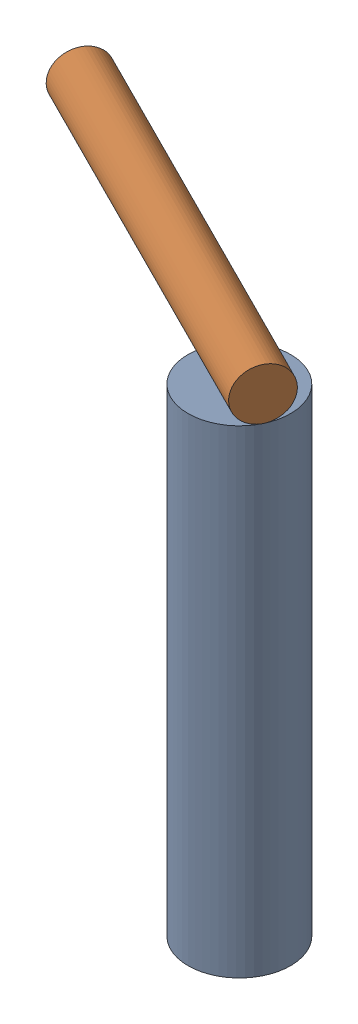
SolidWorks assembly 01-098-00-0, configuration Default. Lengths in mm.
Overall size (73.36 99.52 44.78).
2 component instances, 2 part files, 0 mates.
Components (placement in the parent):
- TROD 0.7500-1x3.5-1: TROD 0.7500-1x3.5 [Default] at origin size (19.05 88.9 19.05)
- 01-099-00-0-1: 01-099-00-0 [Default] at (-59.5351 93.6625 -30.0191) x (0.119593 0.96382 -0.238218) z (0.432432 -0.266552 -0.861367) size (9.53 76.2 9.53)
